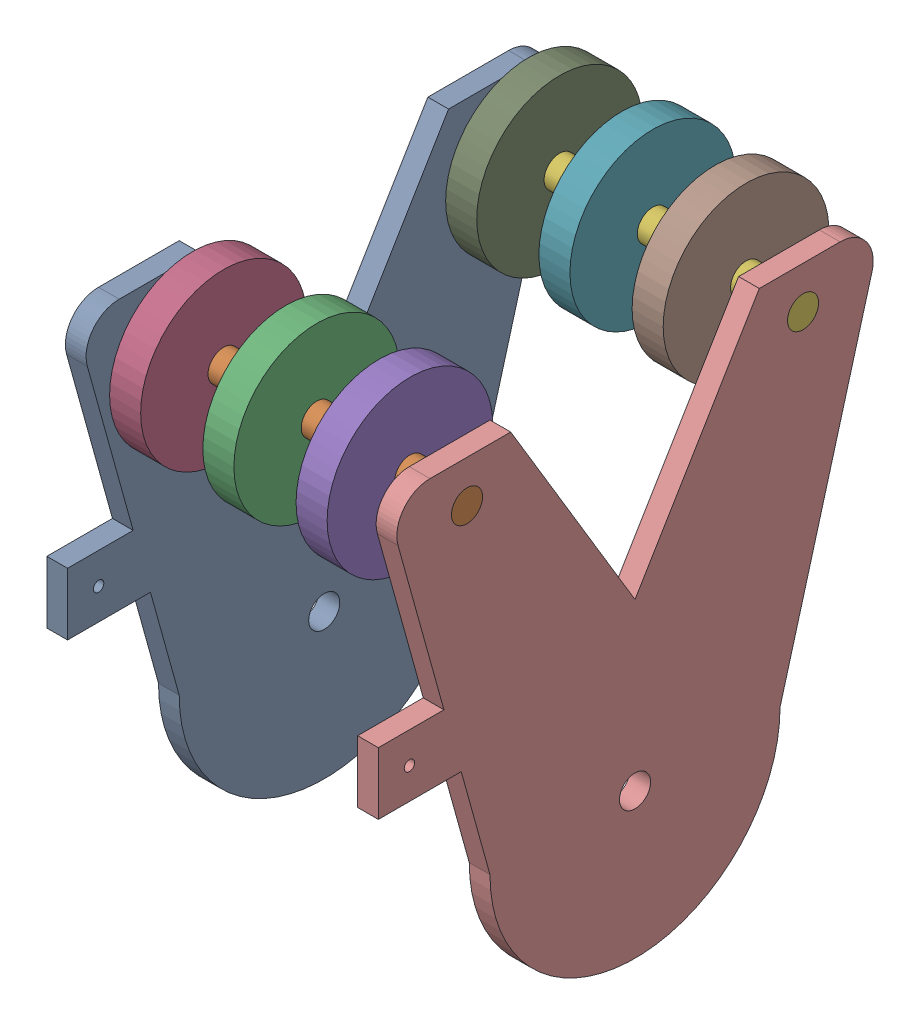
SolidWorks assembly intake_rev1, configuration Default. Lengths in mm.
Overall size (101.6 171.27 155.57).
12 component instances, 3 part files, 7 mates.
Components (placement in the parent):
- endPlate_rev1-1: endPlate_rev1 [Default] at (-50.8 0 0) x (0 -1 0) z (0 0 1) size (158.75 6.35 151.66)
- shaftAndWheelAssm-1: shaftAndWheelAssm [Default] at (0 50.6207 51.4974) x (0 -1 0) z (0 0 1) size (50.8 101.6 50.8)
  - shaft_0.375in-1: shaft_0.375in [Default] at origin size (9.53 101.6 9.53)
  - compliant2inWheel-1: compliant2inWheel [Default] at origin size (50.8 9.53 50.8)
  - compliant2inWheel-2: compliant2inWheel [Default] at (0 -28.575 0) size (50.8 9.53 50.8)
  - compliant2inWheel-3: compliant2inWheel [Default] at (0 28.575 0) size (50.8 9.53 50.8)
- shaftAndWheelAssm-2: shaftAndWheelAssm [Default] at (0 50.6207 -51.4974) x (0 1 0) z (0 0 1) size (50.8 101.6 50.8)
  - shaft_0.375in-1: shaft_0.375in [Default] at origin size (9.53 101.6 9.53)
  - compliant2inWheel-1: compliant2inWheel [Default] at origin size (50.8 9.53 50.8)
  - compliant2inWheel-2: compliant2inWheel [Default] at (0 -28.575 0) size (50.8 9.53 50.8)
  - compliant2inWheel-3: compliant2inWheel [Default] at (0 28.575 0) size (50.8 9.53 50.8)
- endPlate_rev1-2: endPlate_rev1 [Default] at (44.45 0 0) x (0 -1 0) z (0 0 1) size (158.75 6.35 151.66)
Mates (geometry in assembly coordinates):
- Coincident2: coincident aligned: plane of endPlate_rev1-1 through (-113.5468 0 0) normal (0 0 1)
- Coincident3: coincident anti-aligned: plane of endPlate_rev1-1 through (-113.5468 0 0) normal (0 -1 0)
- Concentric1: concentric aligned: cylinder of endPlate_rev1-1 through (-107.1968 50.6207 51.4974) axis (-1 0 0) radius 4.7625; cylinder of shaftAndWheelAssm-1/shaft_0.375in-1 through (-11.9468 50.6207 51.4974) axis (-1 0 0) radius 4.7625
- Coincident4: coincident aligned: plane of endPlate_rev1-1 through (-113.5468 -50.8 0) normal (-1 0 0); plane of shaftAndWheelAssm-1/shaft_0.375in-1 through (-113.5468 50.6207 51.4974) normal (-1 0 0)
- Concentric2: concentric anti-aligned: cylinder of endPlate_rev1-1 through (-44.45 50.6207 -51.4974) axis (-1 0 0) radius 4.7625; cylinder of shaftAndWheelAssm-2/shaft_0.375in-1 through (-50.8 50.6207 -51.4974) axis (1 0 0) radius 4.7625
- Coincident5: coincident aligned: plane of endPlate_rev1-1 through (-50.8 -50.8 0) normal (-1 0 0); plane of shaftAndWheelAssm-2/shaft_0.375in-1 through (-50.8 50.6207 -51.4974) normal (-1 0 0)
- Coincident6: coincident aligned: plane of endPlate_rev1-2 through (50.8 -50.8 0) normal (1 0 0); plane of shaftAndWheelAssm-2/shaft_0.375in-1 through (50.8 50.6207 -51.4974) normal (1 0 0)
